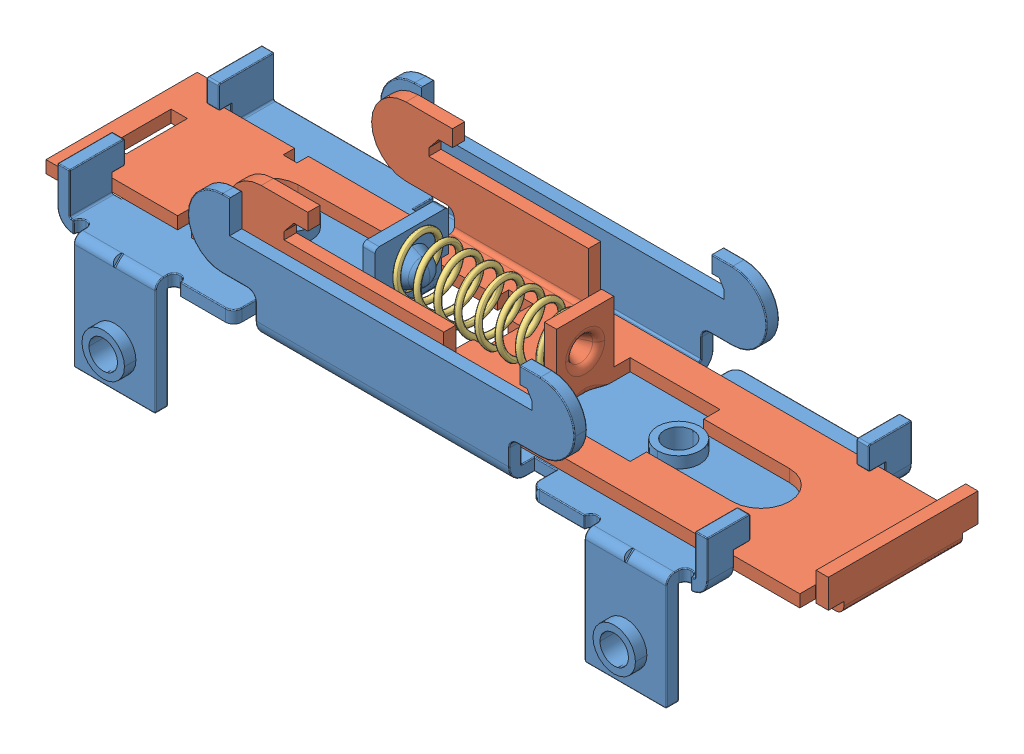
SolidWorks assembly Clip, DIN, Winford DINM30, configuration Default. Lengths in mm.
Overall size (95.6 26.27 27.9).
4 component instances, 3 part files, 0 mates.
Components (placement in the parent):
- dinm30.step-1: dinm30.step [Default] at origin size (95.6 26.27 27.9)
  - DINM30-Clip.step-1: DINM30-Clip.step [Default] at (-12.2332 -1.3871 2.7779) size (79.5 25.9 27.9)
  - DINM30-Shell.step-1: DINM30-Shell.step [Default] at (-12.4332 -1.2871 2.7779) size (95.6 12.29 19.2)
  - DINM30-Spring.step-1: DINM30-Spring.step [Default] at (-13.5086 -0.8734 2.9771) x (0.995815 -0.091388 -0.000013) z (-0.000003 -0.000176 1) size (20.75 9.1 7.34)
